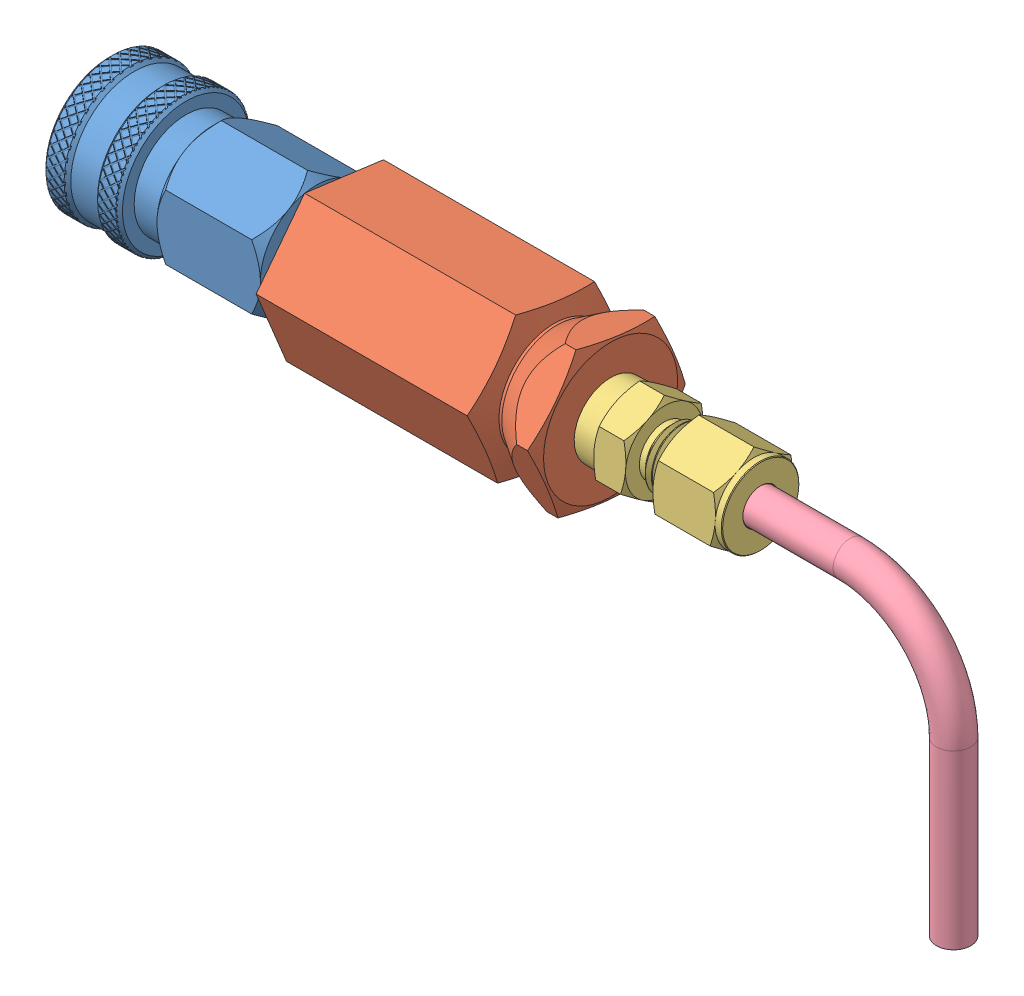
SolidWorks assembly Rocket QD, configuration Default. Lengths in mm.
Overall size (158.79 69.96 35.3).
4 component instances, 4 part files, 6 mates.
Components (placement in the parent):
- QDF -4FNPT-1: QDF -4FNPT [6543K33] at (24.797 22.4876 31.9473) size (38.1 26.13 24.65)
- HP Check Valve-1: HP Check Valve [6543K43] at (15.907 22.4876 31.9473) x (-1 0 0) z (0 -0.924225 -0.381849) size (63.16 25.4 30.98)
- -4S -4MNPT-1: -4S -4MNPT [5182K111] at (106.7556 22.4876 31.9473) x (0 -0.902106 -0.431514) z (1 0 0) size (14.29 16.5 37.85)
- -4 Bend30 HP Fill-1: -4 Bend30 HP Fill [Default] at (124.788 22.4876 31.9473) x (0 -1 0) z (0 0 1) size (53.97 53.97 6.35)
Mates (geometry in assembly coordinates):
- Distance1: distance = 10.16 mm anti-aligned: plane of HP Check Valve-1 through (15.907 22.4876 31.9473) normal (-1 0 0); plane of QDF -4FNPT-1 through (5.747 22.4876 31.9473) normal (1 0 0)
- Concentric2: concentric anti-aligned: cylinder of QDF -4FNPT-1 through (24.797 22.4876 31.9473) axis (-1 0 0) radius 4.5244; cylinder of HP Check Valve-1 through (-7.969 22.4876 31.9473) axis (1 0 0) radius 3.0956
- Concentric3: concentric aligned: cylinder of HP Check Valve-1 through (-7.969 22.4876 31.9473) axis (1 0 0) radius 3.0956; cylinder of -4S -4MNPT-1 through (106.7556 22.4876 31.9473) axis (1 0 0) radius 4.6228
- Distance2: distance = 10.16 mm anti-aligned: plane of HP Check Valve-1 through (79.0696 22.4876 31.9473) normal (1 0 0); plane of -4S -4MNPT-1 through (68.9096 22.4876 31.9473) normal (-1 0 0)
- Coincident2: coincident anti-aligned: plane of -4S -4MNPT-1 through (91.5156 23.8576 29.0831) normal (1 0 0); plane of -4 Bend30 HP Fill-1 through (91.5156 22.4876 31.9473) normal (-1 0 0)
- Concentric4: concentric aligned: cylinder of -4S -4MNPT-1 through (106.7556 22.4876 31.9473) axis (1 0 0) radius 2.3749; cylinder of -4 Bend30 HP Fill-1 through (91.5156 22.4876 31.9473) axis (1 0 0) radius 2.286
